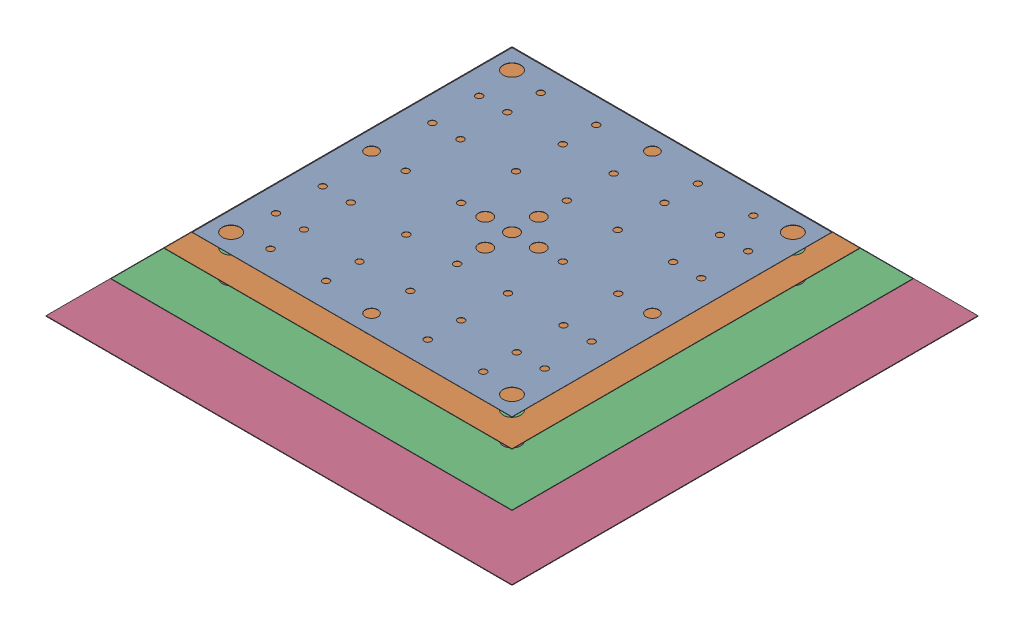
SolidWorks assembly MSR_floor, configuration Default. Lengths in mm.
Overall size (3484 544.5 3484).
4 component instances, 4 part files, 12 mates.
Components (placement in the parent):
- layer5_floor-1: layer5_floor [Default] at (0 -1194 0) size (2390 2 2390)
- layer3_floor-1: layer3_floor [Default] at (0 -1297 0) size (2600 3 2600)
- layer2_floor-1: layer2_floor [Default] at (0 1.5 -1498.5) size (2997 3 2997)
- layer1_floor-1: layer1_floor [Default] at (0 2 -1742) size (3484 4 3484)
Mates (geometry in assembly coordinates):
- Distance1: distance = 1194 mm: plane of assembly; plane of assembly; plane of layer5_floor-1 through (0 -1194 0) normal (0 -1 0)
- Distance2: distance = 1195 mm: plane of assembly; plane of assembly; plane of layer5_floor-1 through (1195 1196 -1195) normal (1 0 0)
- Distance3: distance = 1195 mm: plane of assembly; plane of assembly; plane of layer5_floor-1 through (-1195 1196 1195) normal (0 0 1)
- Distance4: distance = 1297 mm: plane of assembly; plane of assembly; plane of layer3_floor-1 through (0 -1297 0) normal (0 -1 0)
- Distance5: distance = 1300 mm: plane of assembly; plane of assembly; plane of layer3_floor-1 through (1300 1300 -1300) normal (1 0 0)
- Distance6: distance = 1300 mm: plane of assembly; plane of assembly; plane of layer3_floor-1 through (-1300 1300 1300) normal (0 0 1)
- Distance7: distance = 1495.5 mm: plane of assembly; plane of assembly; plane of layer2_floor-1 through (-1498.5 -1495.5 1498.5) normal (0 -1 0)
- Distance8: distance = 1498.5 mm: plane of assembly; plane of assembly; plane of layer2_floor-1 through (1498.5 1498.5 1498.5) normal (1 0 0)
- Distance9: distance = 1498.5 mm: plane of assembly; plane of assembly; plane of layer2_floor-1 through (0 1.5 1498.5) normal (0 0 1)
- Distance10: distance = 1736.5 mm: plane of assembly; plane of assembly; plane of layer1_floor-1 through (-1742 -1736.5 1742) normal (0 -1 0)
- Distance11: distance = 1742 mm: plane of assembly; plane of assembly; plane of layer1_floor-1 through (1742 1740.5 1742) normal (1 0 0)
- Distance12: distance = 1742 mm: plane of assembly; plane of assembly; plane of layer1_floor-1 through (0 2 1742) normal (0 0 1)
